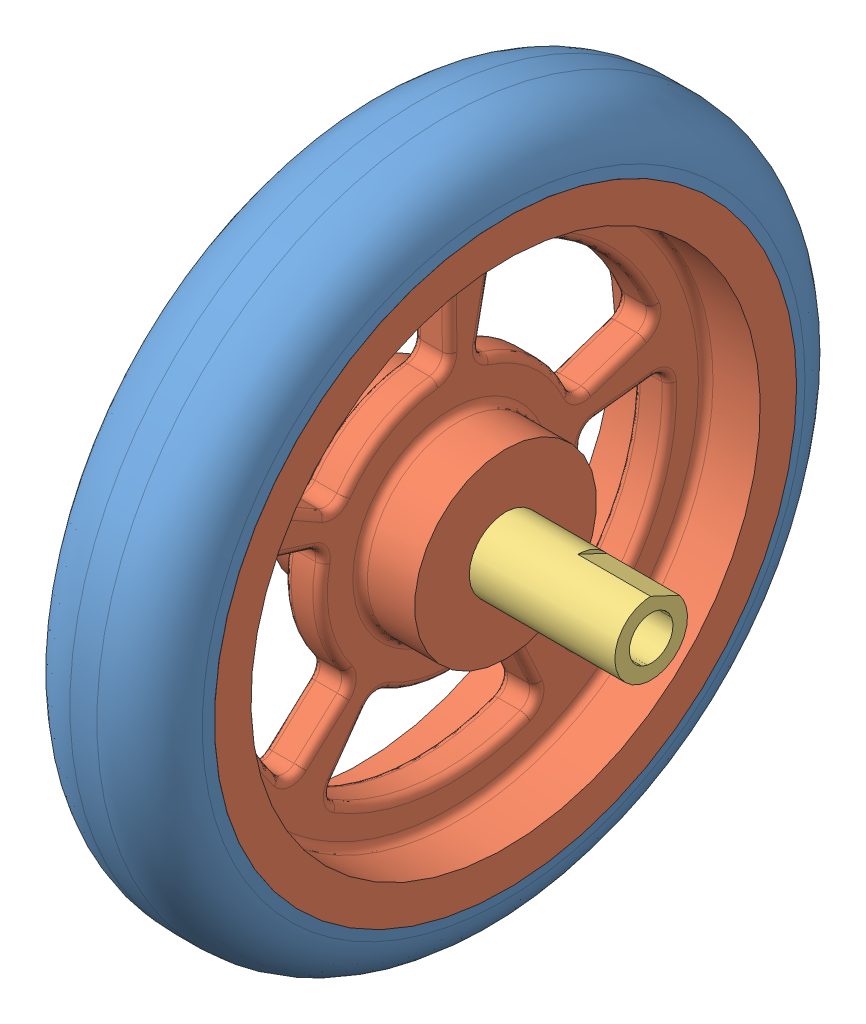
SolidWorks assembly Sub-Assembly - Wheel and Axle, configuration Default. Lengths in mm.
Overall size (60 109.56 109.56).
3 component instances, 3 part files, 4 mates.
Components (placement in the parent):
- Part 4 - Tire-1: Part 4 - Tire [Default] at (36.0514 37.5977 82.131) size (20 96.05 96.05)
- Part 5 - Wheel-1: Part 5 - Wheel [Default] at (36.0514 37.5977 82.131) x (1 0 0) z (0 -0.50832 0.861168) size (20 80 80)
- Axle.SLDPART-1: Axle.SLDPART [Default] at (36.0514 37.5977 82.131) x (0 0.423529 0.905883) z (-1 0 0) size (10 10 60)
Mates (geometry in assembly coordinates):
- Concentric7: concentric: circle of Part 4 - Tire-1; circle of Part 5 - Wheel-1
- Concentric11: concentric: cylinder of Part 5 - Wheel-1 through (36.0514 37.5977 82.131) axis (-1 0 0) radius 5; cylinder of Axle.SLDPART-1 through (6.0514 37.5977 82.131) axis (1 0 0) radius 5
- Coincident1: coincident: plane of Part 5 - Wheel-1 through (36.0514 37.5977 82.131) normal (1 0 0); plane of Axle.SLDPART-1 through (36.0514 37.5977 82.131) normal (-1 0 0)
- Coincident2: coincident: circle of Part 4 - Tire-1; circle of Part 5 - Wheel-1
